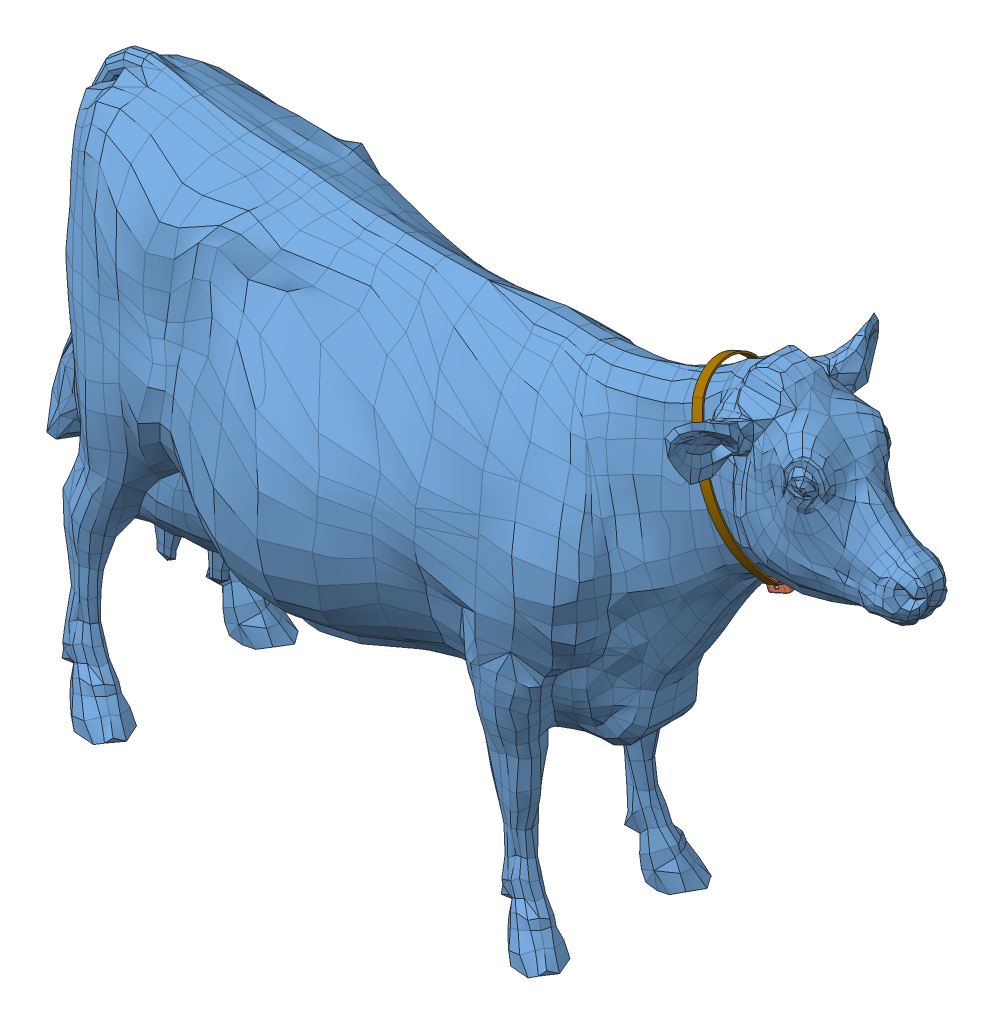
SolidWorks assembly Assembly_Cow_with_Collar_I-CowCare_PFA_2022-2023, configuration Défaut. Lengths in mm.
Overall size (2771.47 1838.71 774.41).
10 component instances, 9 part files, 0 mates.
Components (placement in the parent):
- Cow_I-CowCare_PFA_2022-2023-1: Cow_I-CowCare_PFA_2022-2023 [Défaut] at (-112.5009 188.5371 2771.4741) size (2771.47 1838.71 774.41)
- Assembly_Collar_I-CowCare_PFA_2022-2023-1: Assembly_Collar_I-CowCare_PFA_2022-2023 [Défaut] at (738.2347 396.8666 2832.3609) x (0.009891 -0.233952 0.972198) z (0.960714 0.271902 0.055657) size (410.03 600.67 127.8)
  - Collar_Box_I-CowCare_PFA_2022-2023-1: Collar_Box_I-CowCare_PFA_2022-2023 [Défaut] at (-57.1035 129.9382 251.1481) x (0.962421 -0.16686 0.21425) z (0.219802 0.015324 -0.975424) size (106 30 65)
  - CR123A  Battery Holder.step-1: CR123A  Battery Holder.step [Défaut] at (-20.8805 121.4201 236.971) x (-0.219802 -0.015324 0.975424) z (-0.962421 0.16686 -0.21425) size (43.32 18.5 18.25)
  - Boita2_I-CowCare_PFA_2022-2023-1: Boita2_I-CowCare_PFA_2022-2023 [Défaut] at (-57.1035 129.9382 251.1481) x (0.962421 -0.16686 0.21425) z (0.219802 0.015324 -0.975424) size (90 6.8 65)
  - Accelerometer_#ADXL377Z_I-CowCare_PFA_2022-2023-1: Accelerometer_#ADXL377Z_I-CowCare_PFA_2022-2023 [Défaut] at (-62.6426 136.6714 281.2742) x (0.962421 -0.16686 0.21425) z (0.219802 0.015324 -0.975424) size (20.4 20.4 4.3)
  - Temp_Sensor_I-CowCare_PFA_2022-2023-1: Temp_Sensor_I-CowCare_PFA_2022-2023 [Défaut] at (-52.8215 124.2296 252.0233) x (0.219802 0.015324 -0.975424) z (-0.159476 -0.985862 -0.051424) size (17.5 11 5.8)
  - CR_123A_Battery_I-CowCare_PFA_2022-2023-1: CR_123A_Battery_I-CowCare_PFA_2022-2023 [Standard] at (-36.4857 132.2583 272.0451) x (0.956434 0.193559 0.218563) z (-0.192151 0.980969 -0.027888) size (17 34.5 17)
  - ESP32_I-CowCare_PFA_2022-2023-1: ESP32_I-CowCare_PFA_2022-2023 [Predeterminado] at (-75.9884 133.6177 246.9504) x (-0.219802 -0.015324 0.975424) z (-0.962421 0.16686 -0.21425) size (51.5 14.5 28.3)
  - Collier_I-CowCare_PFA_2022-2023-1: Collier_I-CowCare_PFA_2022-2023 [Défaut] at (-105.1895 -136.0664 251.5114) x (-0.962421 0.16686 -0.21425) z (0.219802 0.015324 -0.975424) size (328.41 547.82 30)
